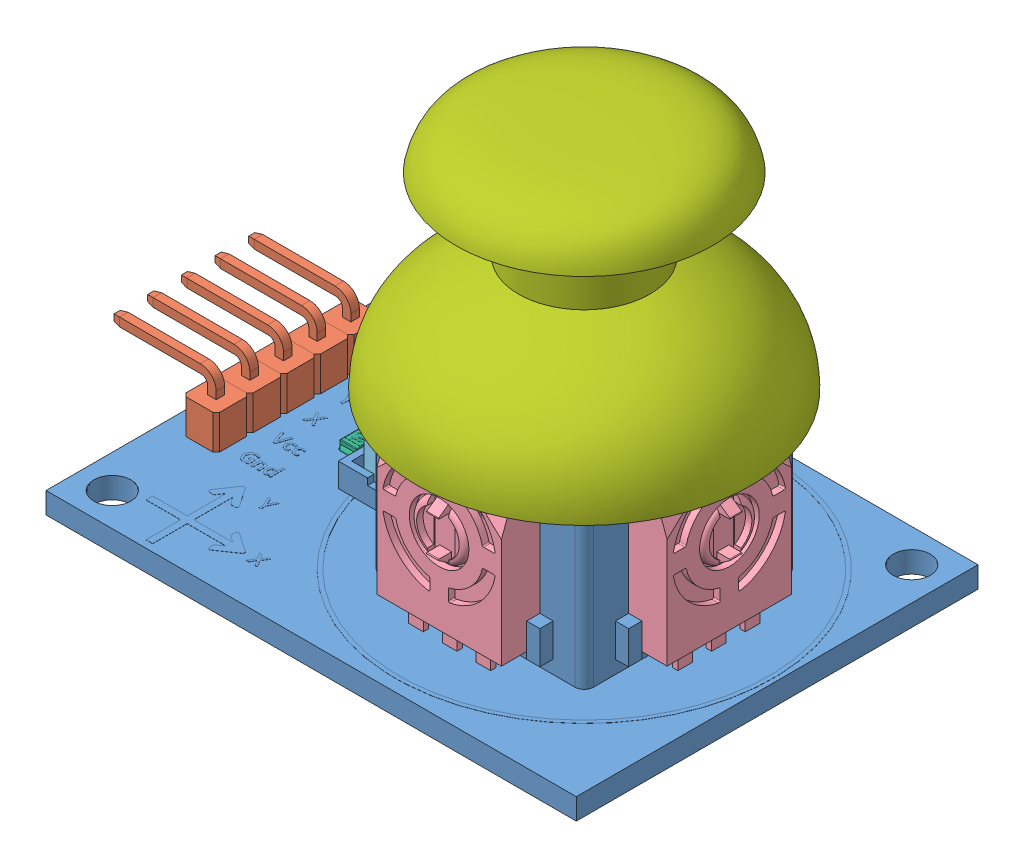
SolidWorks assembly PS2 Joystick Module, configuration Default. Lengths in mm.
Overall size (44.71 32.6 30.3).
16 component instances, 7 part files, 0 mates.
Components (placement in the parent):
- ps2board-1: ps2board [Default] at origin size (40 14.1 30.3)
- 90headerMale-1: 90headerMale [Default] at (-17.23 1.6 -2.54) x (0 0 -1) z (1 0 0) size (2.54 7.1 8.75)
- 90headerMale-2: 90headerMale [Default] at (-17.23 1.6 0) x (0 0 -1) z (1 0 0) size (2.54 7.1 8.75)
- 90headerMale-3: 90headerMale [Default] at (-17.23 1.6 -5.08) x (0 0 -1) z (1 0 0) size (2.54 7.1 8.75)
- 90headerMale-4: 90headerMale [Default] at (-17.23 1.6 2.54) x (0 0 -1) z (1 0 0) size (2.54 7.1 8.75)
- 90headerMale-5: 90headerMale [Default] at (-17.23 1.6 5.08) x (0 0 -1) z (1 0 0) size (2.54 7.1 8.75)
- solder-1: solder [Default] at (-17.241 0 -2.545) x (-0.837169 0 -0.546944) z (-0.546944 0 0.837169) size (1.17 0.65 1.17)
- solder-2: solder [Default] at (-17.241 0 -0.005) x (-0.837169 0 -0.546944) z (-0.546944 0 0.837169) size (1.17 0.65 1.17)
- solder-3: solder [Default] at (-17.241 0 2.535) x (-0.837169 0 -0.546944) z (-0.546944 0 0.837169) size (1.17 0.65 1.17)
- solder-4: solder [Default] at (-17.241 0 -5.085) x (-0.837169 0 -0.546944) z (-0.546944 0 0.837169) size (1.17 0.65 1.17)
- solder-5: solder [Default] at (-17.241 0 5.075) x (-0.837169 0 -0.546944) z (-0.546944 0 0.837169) size (1.17 0.65 1.17)
- verticalTrimmer103-1: verticalTrimmer103 [Default] at (13.5 9.5 0) x (0 0 -1) z (1 0 0) size (9.4 15 3.4)
- verticalTrimmer103-2: verticalTrimmer103 [Default] at (5.45 9.5 8.05) size (9.4 15 3.4)
- pushButton1_5mm-1: pushButton1_5mm [Default] at (-5.2063 1.3 0) x (0 0 1) z (-1 0 0) size (6.77 7.95 6)
- smdResistor103-1: smdResistor103 [Default] at (-11.01 1.6 0.2209) x (0 0 -1) z (1 0 0) size (2.54 0.62 1.34)
- Thumbstick-1: Thumbstick [Default] at (5.45 13.35 0) x (0.999999 0 -0.0013) z (0.0013 0 0.999999) size (25.14 17.6 25.14)
